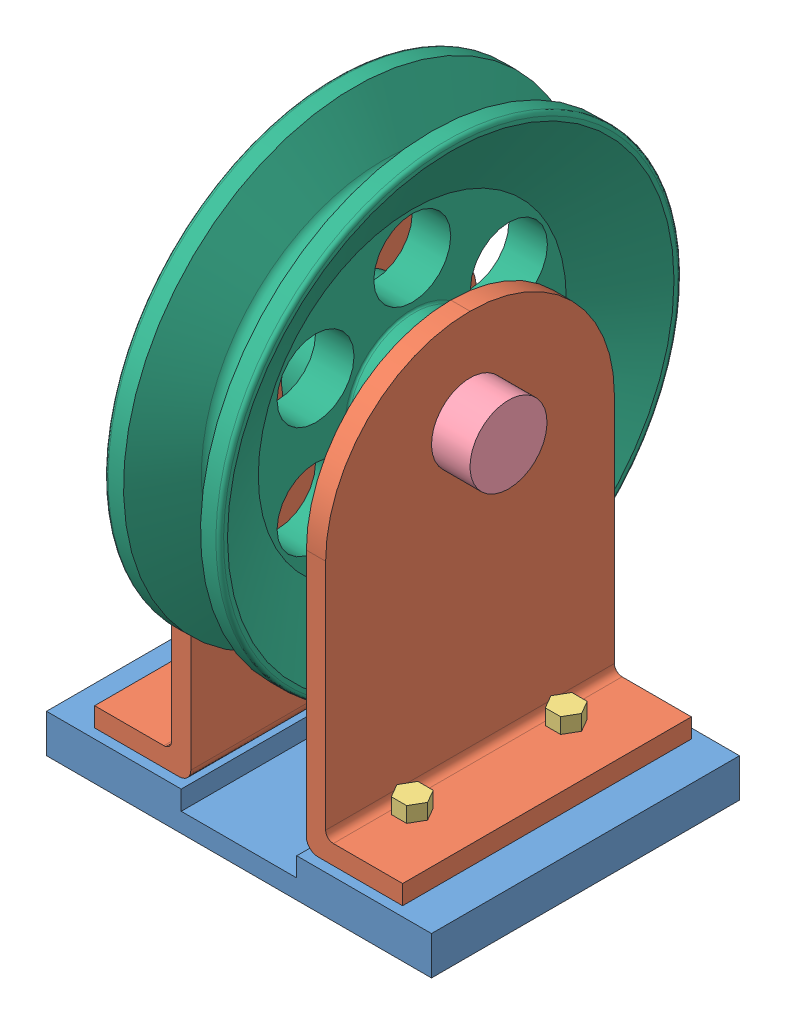
SolidWorks assembly Pulley-assembly, configuration Default. Lengths in mm.
Overall size (2540 3821.7 3048).
10 component instances, 6 part files, 25 mates.
Components (placement in the parent):
- Base Plate-1: Base Plate [Default] at (960.6469 1378.9175 1820.4883) size (2540 254 2032)
- Bracket-5: Bracket [Default] at (1341.6469 1632.9175 867.9883) x (0 0 -1) z (1 0 0) size (1905 2724.15 698.5)
- Bracket-6: Bracket [Default] at (579.6469 1632.9175 2772.9883) x (0 0 1) z (-1 0 0) size (1905 2724.15 698.5)
- Bolt-1: Bolt [Default] at (1595.6469 1759.9175 1312.4883) size (202.45 355.6 175.33)
- Bolt-2: Bolt [Default] at (1595.6469 1759.9175 2328.4883) size (202.45 355.6 175.33)
- Bolt-3: Bolt [Default] at (325.6469 1759.9175 1312.4883) size (202.45 355.6 175.33)
- Bolt-4: Bolt [Default] at (325.6469 1759.9175 2328.4883) size (202.45 355.6 175.33)
- Axle-3: Axle [Default] at (452.6469 3664.9175 1820.4883) x (0 0 1) z (0 -1 0) size (670.56 1816.1 609.6)
- Key-1: Key [Default] at (960.6469 3817.3175 1820.4883) size (635 203.2 152.4)
- Pulley-1: Pulley [Default] at (960.6469 3676.6169 1820.4883) x (0 0 1) z (0 -1 0) size (3048 762 3048)
Mates (geometry in assembly coordinates):
- Coincident1: coincident: axis of Base Plate-1 through (1595.6469 1378.9175 2328.4883) axis (0 1 0); axis of Bracket-5 through (1595.6469 1632.9175 2328.4883) axis (0 1 0)
- Coincident3: coincident: plane of Base Plate-1 through (960.6469 1632.9175 1820.4883) normal (0 1 0); plane of Bracket-5 through (1976.6469 1632.9175 2772.9883) normal (0 -1 0)
- Coincident4: coincident: axis of Base Plate-1 through (325.6469 1378.9175 1312.4883) axis (0 1 0); axis of Bracket-6 through (325.6469 1632.9175 1312.4883) axis (0 1 0)
- Coincident5: coincident: plane of Base Plate-1 through (960.6469 1632.9175 1820.4883) normal (0 1 0); plane of Bracket-6 through (-55.3531 1632.9175 867.9883) normal (0 -1 0)
- Coincident6: coincident: axis of Bracket-5 through (1595.6469 1632.9175 1312.4883) axis (0 1 0); axis of Bolt-1 through (1595.6469 1505.9175 1312.4883) axis (0 1 0)
- Coincident7: coincident: plane of Bracket-5 through (1468.6469 1759.9175 2772.9883) normal (0 1 0); plane of Bolt-1 through (1595.6469 1759.9175 1312.4883) normal (0 -1 0)
- Coincident8: coincident: axis of Bracket-5 through (1595.6469 1632.9175 2328.4883) axis (0 1 0); axis of Bolt-2 through (1595.6469 1505.9175 2328.4883) axis (0 1 0)
- Coincident9: coincident: plane of Bracket-5 through (1468.6469 1759.9175 2772.9883) normal (0 1 0); plane of Bolt-2 through (1595.6469 1759.9175 2328.4883) normal (0 -1 0)
- Coincident10: coincident: axis of Bracket-6 through (325.6469 1632.9175 1312.4883) axis (0 1 0); axis of Bolt-3 through (325.6469 1505.9175 1312.4883) axis (0 1 0)
- Coincident11: coincident: plane of Bracket-6 through (452.6469 1759.9175 867.9883) normal (0 1 0); plane of Bolt-3 through (325.6469 1759.9175 1312.4883) normal (0 -1 0)
- Coincident12: coincident: axis of Bracket-6 through (325.6469 1632.9175 2328.4883) axis (0 1 0); axis of Bolt-4 through (325.6469 1505.9175 2328.4883) axis (0 1 0)
- Coincident13: coincident: plane of Bracket-6 through (452.6469 1759.9175 867.9883) normal (0 1 0); plane of Bolt-4 through (325.6469 1759.9175 2328.4883) normal (0 -1 0)
- Lock2: lock: unknown of Base Plate-1; unknown of Bracket-6
- Lock3: lock: unknown of Bracket-6; unknown of Bolt-3
- Lock4: lock: unknown of Bracket-6; unknown of Bolt-4
- Lock5: lock: unknown of Base Plate-1; unknown of Bracket-5
- Lock6: lock: unknown of Bracket-5; unknown of Bolt-2
- Lock7: lock: unknown of Bracket-5; unknown of Bolt-1
- Coincident23: coincident: axis of Bracket-6 through (579.6469 3664.9175 1820.4883) axis (-1 0 0); axis of Axle-3 through (1722.6469 3664.9175 1820.4883) axis (-1 0 0)
- Coincident24: coincident: plane of Bracket-6 through (452.6469 4299.9175 867.9883) normal (-1 0 0); plane of Axle-3 through (452.6469 3664.9175 1820.4883) normal (1 0 0)
- Coincident26: coincident: plane of Axle-3 through (1278.1469 3817.3175 1896.6883) normal (0 0 -1); plane of Key-1 through (1278.1469 4020.5175 1896.6883) normal (0 0 1)
- Lock8: lock: unknown of Axle-3; unknown of Key-1
- Coincident33: coincident: plane of Key-1 through (960.6469 4020.5175 1820.4883) normal (0 1 0); plane of Pulley-1 through (1341.6469 4020.5175 1744.2883) normal (0 -1 0)
- Coincident34: coincident: plane of Key-1 through (1278.1469 4020.5175 1896.6883) normal (0 0 1); plane of Pulley-1 through (1341.6469 4020.5175 1896.6883) normal (0 0 -1)
- Coincident35: coincident: plane of Base Plate-1 through (960.6469 1378.9175 1820.4883) normal (1 0 0); plane of Pulley-1 through (960.6469 3676.6169 1820.4883) normal (-1 0 0)
